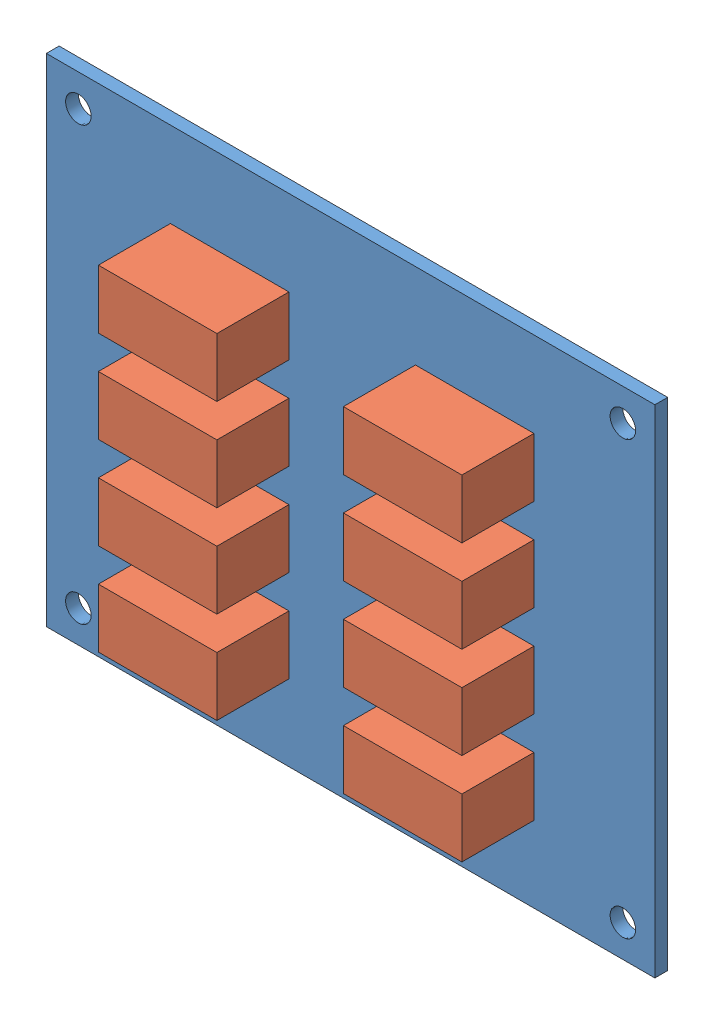
SolidWorks assembly RLY08BoardAssembly, configuration Default. Lengths in mm.
Overall size (76 62 10.6).
9 component instances, 2 part files, 3 mates.
Components (placement in the parent):
- RLY08Board-1: RLY08Board [Default] at (-74.4697 12.5942 29.9403) size (76 62 1.6)
- Relay-ED2-5NU-1: Relay-ED2-5NU [Default] at (-96.9697 -8.9058 31.5403) size (14.8 7.35 9)
- Relay-ED2-5NU-2: Relay-ED2-5NU [Default] at (-96.9697 2.5942 31.5403) size (14.8 7.35 9)
- Relay-ED2-5NU-3: Relay-ED2-5NU [Default] at (-96.9697 14.0942 31.5403) size (14.8 7.35 9)
- Relay-ED2-5NU-4: Relay-ED2-5NU [Default] at (-96.9697 25.5942 31.5403) size (14.8 7.35 9)
- Relay-ED2-5NU-5: Relay-ED2-5NU [Default] at (-66.3697 -8.9058 31.5403) size (14.8 7.35 9)
- Relay-ED2-5NU-6: Relay-ED2-5NU [Default] at (-66.3697 2.5942 31.5403) size (14.8 7.35 9)
- Relay-ED2-5NU-7: Relay-ED2-5NU [Default] at (-66.3697 14.0942 31.5403) size (14.8 7.35 9)
- Relay-ED2-5NU-8: Relay-ED2-5NU [Default] at (-66.3697 25.5942 31.5403) size (14.8 7.35 9)
Mates (geometry in assembly coordinates):
- Coincident1: coincident: plane of RLY08Board-1 through (-74.4697 12.5942 31.5403) normal (0 0 1); plane of Relay-ED2-5NU-1 through (-101.696 -8.9058 31.5403) normal (0 0 -1)
- Distance1: distance = 9.5 mm: plane of Relay-ED2-5NU-1 through (-96.9697 -8.9058 40.5403) normal (0 -1 0); plane of RLY08Board-1 through (-112.4697 -18.4058 31.5403) normal (0 -1 0)
- Distance2: distance = 15.5 mm aligned: plane of RLY08Board-1 through (-112.4697 43.5942 31.5403) normal (-1 0 0); plane of Relay-ED2-5NU-1 through (-96.9697 -8.9058 40.5403) normal (-1 0 0)
